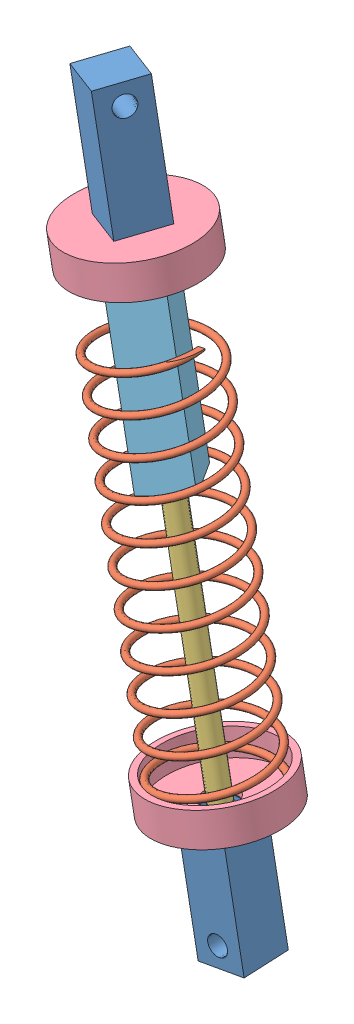
SolidWorks assembly suspension rear right, configuration Default. Lengths in mm.
Overall size (35.66 112.21 26.98).
7 component instances, 5 part files, 12 mates.
Components (placement in the parent):
- ball joint-1: ball joint [Default] at (-14.1918 89.0976 2.2248) x (0.414974 0.088709 -0.905498) z (0.896141 0.132162 0.423633) size (7 19 7)
- ball joint-2: ball joint [Default] at (-2.516 15.796 0.3944) x (0.987183 0.157832 -0.023648) z (-0.027237 0.020617 -0.999416) size (7 19 7)
- Spring-1: Spring [Default] at (-2.6733 16.7833 0.4191) x (0.986838 0.158042 -0.034256) z (0.037715 -0.018941 0.999109) size (17.25 46.09 19.28)
- suspension shaft-1: suspension shaft [Default] at (-10.6983 67.1652 1.6771) x (0.097169 0.040309 -0.994451) z (-0.982766 -0.153985 -0.102269) size (3 65 3)
- washer-1: washer [Default] at (-2.516 15.796 0.3944) x (-0.692989 -0.092528 -0.714986) z (0.70359 0.129517 -0.698704) size (19 5 19)
- washer-2: washer [Default] at (-14.1918 89.0976 2.2248) x (0.152778 0.048982 -0.987046) z (-0.975669 -0.151449 -0.158533) size (19 5 19)
- suspension shaft 1-1: suspension shaft 1 [Default] at (-15.607 97.9829 2.4467) x (-0.55331 -0.067402 -0.830244) z (-0.817997 -0.144198 0.556855) size (7 42 7)
Mates (geometry in assembly coordinates):
- Concentric3: concentric anti-aligned: cylinder of suspension shaft-1 through (-0.4769 2.9939 0.0748) axis (-0.157253 0.987251 0.024652) radius 1.5; cylinder of washer-1 through (-2.6733 16.7833 0.4191) axis (0.157253 -0.987251 -0.024652) radius 9.5
- Concentric4: concentric aligned: cylinder of suspension shaft-1 through (-0.4769 2.9939 0.0748) axis (-0.157253 0.987251 0.024652) radius 1.5; cylinder of washer-2 through (-14.0345 88.1104 2.2001) axis (-0.157253 0.987251 0.024652) radius 2.5
- Coincident4: coincident: point of ball joint-2
- Coincident8: coincident anti-aligned: plane of Spring-1 through (-2.6733 16.7833 0.4191) normal (0.157253 -0.987251 -0.024652); plane of washer-1 through (-2.6733 16.7833 0.4191) normal (-0.157253 0.987251 0.024652)
- Concentric7: concentric aligned: line of Spring-1 through (-2.6733 16.7833 0.4191) axis (-0.157253 0.987251 0.024652); cylinder of suspension shaft-1 through (-0.4769 2.9939 0.0748) axis (-0.157253 0.987251 0.024652) radius 1.5
- LimitDistance1: limit distance = 73.2482 mm aligned: plane of washer-1 through (-2.6733 16.7833 0.4191) normal (-0.157253 0.987251 0.024652); plane of washer-2 through (-14.1918 89.0976 2.2248) normal (-0.157253 0.987251 0.024652)
- Concentric8: concentric aligned: cylinder of ball joint-2 through (-0.4718 2.9618 0.074) axis (-0.157253 0.987251 0.024652) radius 2.375; cylinder of suspension shaft-1 through (-0.4769 2.9939 0.0748) axis (-0.157253 0.987251 0.024652) radius 1.5
- Coincident9: coincident anti-aligned: plane of ball joint-2 through (-2.516 15.796 0.3944) normal (-0.157253 0.987251 0.024652); plane of washer-1 through (-2.516 15.796 0.3944) normal (0.157253 -0.987251 -0.024652)
- Coincident10: coincident anti-aligned: plane of washer-2 through (-14.0345 88.1104 2.2001) normal (0.157253 -0.987251 -0.024652); plane of suspension shaft 1-1 through (-14.0345 88.1104 2.2001) normal (-0.157253 0.987251 0.024652)
- Concentric9: concentric aligned: cylinder of washer-2 through (-14.0345 88.1104 2.2001) axis (-0.157253 0.987251 0.024652) radius 2.5; cylinder of suspension shaft 1-1 through (-14.0345 88.1104 2.2001) axis (-0.157253 0.987251 0.024652) radius 2
- Coincident11: coincident anti-aligned: plane of ball joint-1 through (-14.1918 89.0976 2.2248) normal (0.157253 -0.987251 -0.024652); plane of washer-2 through (-14.1918 89.0976 2.2248) normal (-0.157253 0.987251 0.024652)
- Concentric10: concentric anti-aligned: cylinder of ball joint-1 through (-16.2361 101.9319 2.5453) axis (0.157253 -0.987251 -0.024652) radius 2.375; cylinder of suspension shaft 1-1 through (-14.0345 88.1104 2.2001) axis (-0.157253 0.987251 0.024652) radius 2
